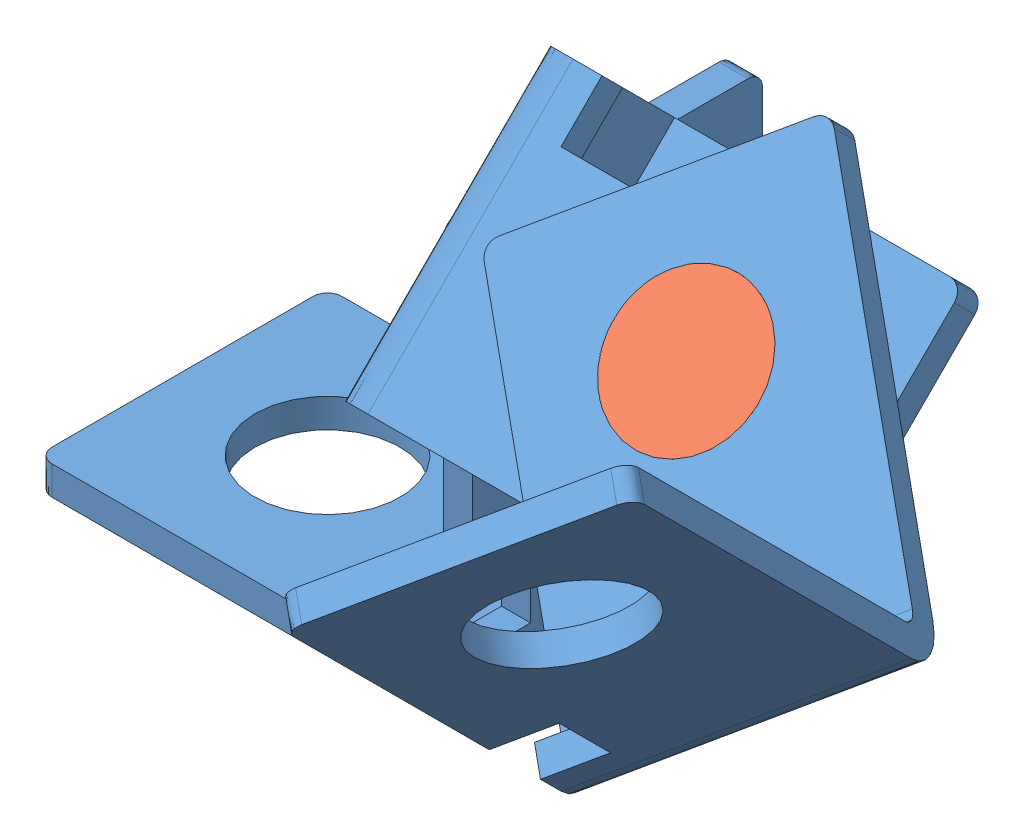
SolidWorks assembly darmaly-LAB12-Assembly, configuration Default. Lengths in mm.
Overall size (72.21 66.06 65.2).
5 component instances, 2 part files, 13 mates.
Components (placement in the parent):
- Bracket-2: Bracket [Default] at (30 0 10) x (0 0 1) z (-1 0 0) size (20 30 30)
- Pin-1: Pin [Default] at (33 20 10) x (0 1 0) z (0 0 1) size (10 5 10)
- Bracket-3: Bracket [Default] at (31 34.1421 24.1421) x (0 0.707107 -0.707107) z (0 -0.707107 -0.707107) size (20 30 30)
- Pin-2: Pin [Default] at (51 32.7279 22.7279) x (1 0 0) z (0 -0.707107 0.707107) size (10 5 10)
- Bracket-4: Bracket [Default] at (65.1421 24.8492 34.8492) x (-0.707107 -0.5 0.5) z (-0.707107 0.5 -0.5) size (20 30 30)
Mates (geometry in assembly coordinates):
- Coincident6: coincident anti-aligned: plane of Bracket-2 through (30 0 0) normal (0 0 -1)
- Coincident7: coincident anti-aligned: plane of Bracket-2 through (0 0 20) normal (-1 0 0)
- Coincident8: coincident anti-aligned: plane of Bracket-2 through (0 0 20) normal (0 -1 0)
- Concentric1: concentric anti-aligned: cylinder of Bracket-2 through (38 20 10) axis (-1 0 0) radius 5; cylinder of Pin-1 through (28 20 10) axis (1 0 0) radius 5
- Coincident9: coincident aligned: plane of Bracket-2 through (28 0 20) normal (-1 0 0); plane of Pin-1 through (28 20 10) normal (-1 0 0)
- Distance3: distance = 1 mm anti-aligned: plane of Bracket-3 through (31 20 -4.1421) normal (-1 0 0); plane of Bracket-2 through (30 0 20) normal (1 0 0)
- Concentric2: concentric aligned: cylinder of Pin-1 through (28 20 10) axis (1 0 0) radius 5; cylinder of Bracket-3 through (23 20 10) axis (1 0 0) radius 5
- Angle1: planar angle = 0.785398 rad aligned: line of Bracket-3 through (31 6.565 10.7071) axis (0 0.707107 0.707107); line of Bracket-2 through (30 10 20) axis (0 1 0)
- Concentric3: concentric aligned: cylinder of Bracket-3 through (51 39.799 29.799) axis (0 -0.707107 -0.707107) radius 5; cylinder of Pin-2 through (51 36.2635 26.2635) axis (0 -0.707107 -0.707107) radius 5
- Coincident12: coincident aligned: plane of Bracket-3 through (31 39.799 15.6569) normal (0 -0.707107 -0.707107); plane of Pin-2 through (51 32.7279 22.7279) normal (0 -0.707107 -0.707107)
- Concentric4: concentric anti-aligned: cylinder of Pin-2 through (51 36.2635 26.2635) axis (0 -0.707107 -0.707107) radius 5; cylinder of Bracket-4 through (51 29.1924 19.1924) axis (0 0.707107 0.707107) radius 5
- Coincident13: coincident aligned: plane of Pin-2 through (51 36.2635 26.2635) normal (0 0.707107 0.707107); plane of Bracket-4 through (36.9137 37.1511 25.3758) normal (0 0.707107 0.707107)
- Angle2: planar angle = 0.785398 rad aligned: line of Bracket-4 through (37.565 34.3492 25.3492) axis (0.707107 -0.5 0.5); line of Bracket-3 through (34 27.0711 31.2132) axis (1 0 0)
